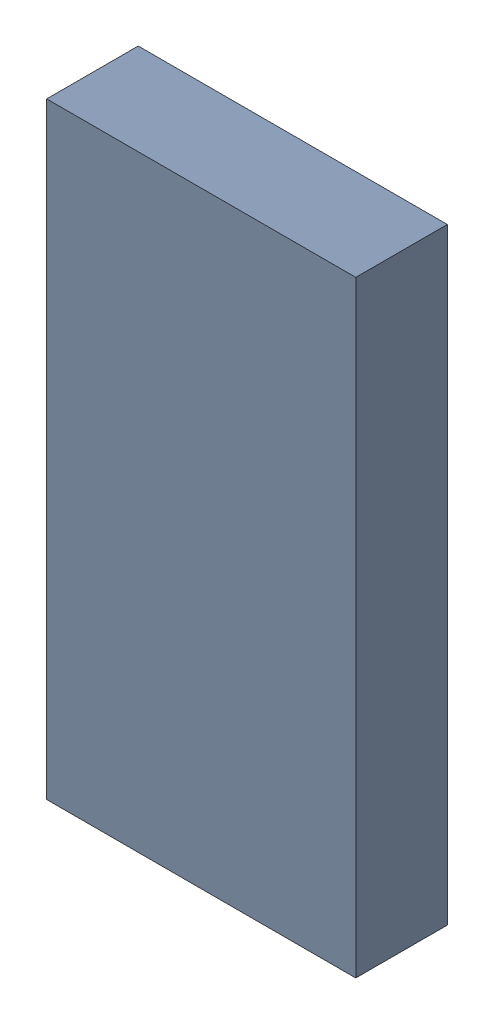
SolidWorks assembly AMS-1, configuration Default. Lengths in mm.
Overall size (3.43 6.73 1.02).
2 component instances, 1 part files, 0 mates.
Components (placement in the parent):
- 678510320-1: 678510320 [Default] at (41.1901 60.7627 -1.6815) size (3.43 6.73 1.02)
  - Extruded (20)-1: Extruded (20) [Default] at origin size (3.43 6.73 1.02)
